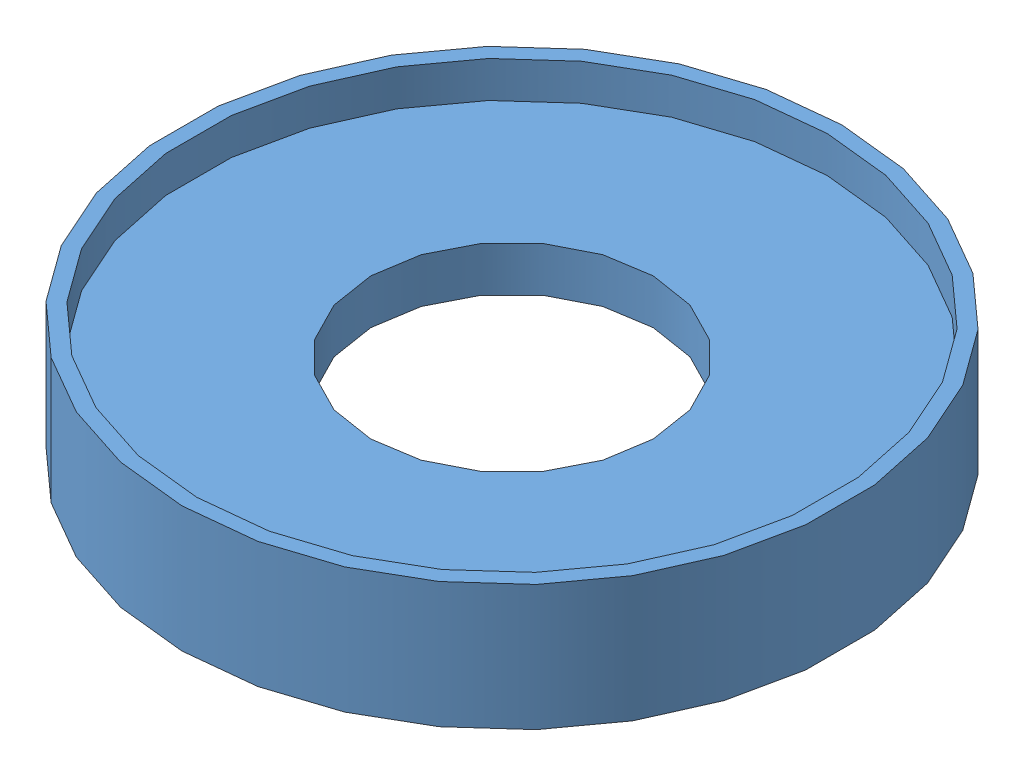
SolidWorks assembly B2717, configuration Default. Lengths in mm.
Overall size (89 16.96 89).
11 component instances, 3 part files, 6 mates.
Components (placement in the parent):
- B2574-1: B2574 [Default] at origin size (89 16.96 89)
- B1995-1: B1995 [7] at (0 6.05 0) x (0 0 -1) z (0 1 0) size (239.39 157.62 264.32) (suppressed, hidden)
  - B1998-1: B1998 [X7] x (0 0 -1) z (1 0 0)
  - B1998-2: B1998 [Y7] x (0 0 1) z (0 1 0)
  - B1998-3: B1998 [Z7] at origin
  - B1999-2: B1999 [100] at (0 0 197.2124) x (0 0 -1) z (0.268665 -0.963234 0)
- B1995-2: B1995 [T] at (0 100.05 0) x (0 0 -1) z (0 1 0) size (239.39 157.62 264.32) (suppressed, hidden)
  - B1998-1: B1998 [XT] x (0 0 -1) z (1 0 0)
  - B1998-2: B1998 [YT] x (0 0 1) z (0 1 0)
  - B1998-3: B1998 [ZT] at origin
  - B1999-2: B1999 [100] at (0 0 197.2124) x (0 0 -1) z (0.268665 -0.963234 0)
Mates (geometry in assembly coordinates):
- Coincident3: coincident aligned: plane of B1995-1; plane of B2574-1 through (0 6.05 -42.5) normal (0 1 0)
- Coincident4: coincident anti-aligned: plane of B1995-1; plane of assembly
- Coincident6: coincident anti-aligned: plane of B1995-1; plane of assembly
- Coincident9: coincident anti-aligned: plane of B1995-2; plane of assembly
- Coincident10: coincident anti-aligned: plane of B1995-2; plane of assembly
- Distance1: distance = 94 mm: point of B1995-1; point of B1995-2
